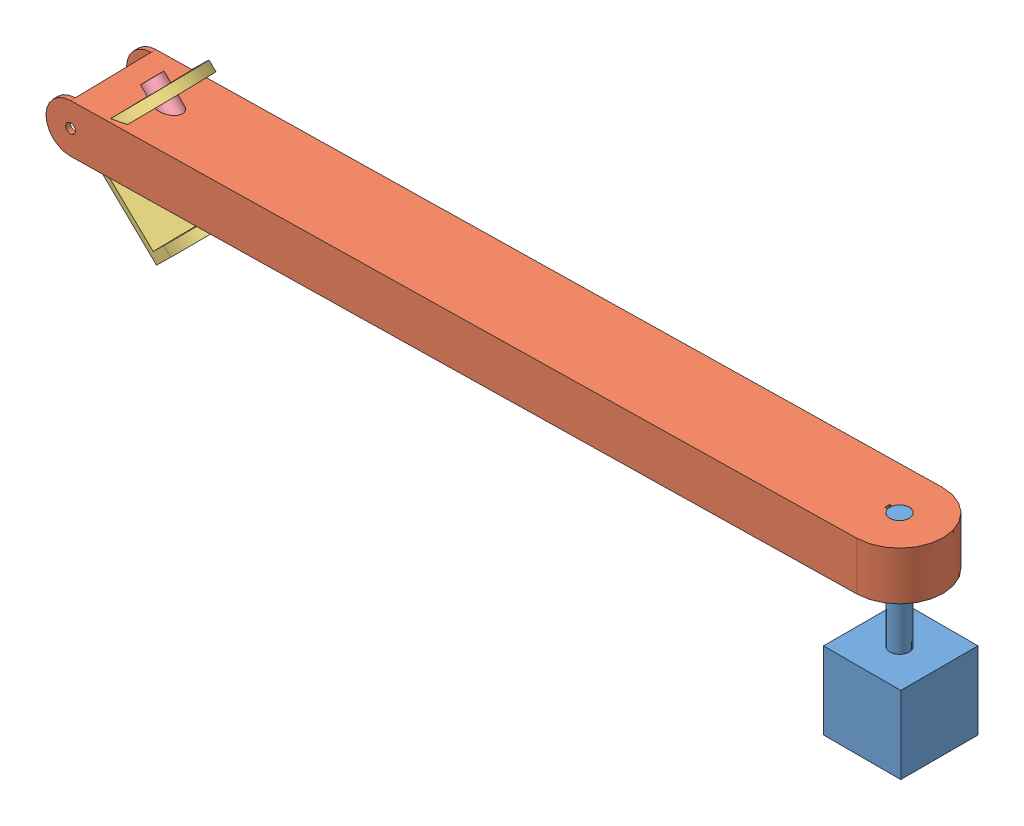
SolidWorks assembly ExcavatorAssm, configuration Default. Lengths in mm.
Overall size (553.4 151.03 78.88).
4 component instances, 4 part files, 6 mates.
Components (placement in the parent):
- joint1barebonesmotor-1: joint1barebonesmotor [Default] at origin size (50.8 127 50.8)
- PreliminaryLink1-1: PreliminaryLink1 [Default] at (-0.1864 110.453 -10.2121) x (0.01825 0 0.999833) z (0 -1 0) size (57.15 552.45 31.75)
- link2pinbracket-1: link2pinbracket [Default] at (-422.7408 90.0407 1.1416) x (-0.208545 -0.225877 0.951572) z (-0.706989 0.707107 0.012905) size (63.5 57.15 69.85)
- link2pin-1: link2pin [Default] at (-428.834 83.8265 7.8276) x (-0.060083 -0.078234 0.995123) z (-0.704668 -0.702766 -0.097796) size (12.7 76.2 12.7)
Mates (geometry in assembly coordinates):
- Concentric1: concentric anti-aligned: cylinder of joint1barebonesmotor-1 through (0 127 0) axis (0 -1 0) radius 6.35; cylinder of PreliminaryLink1-1 through (0 77.2895 0) axis (0 1 0) radius 6.35
- Coincident1: coincident aligned: plane of joint1barebonesmotor-1 through (0 127 0) normal (0 1 0); plane of PreliminaryLink1-1 through (-508.1018 127 -0.941) normal (0 1 0)
- Concentric2: concentric: cylinder of PreliminaryLink1-1 through (158.4346 79.9197 394.3633) axis (0.263601 0.707107 0.656136) radius 6.35; cylinder of link2pin-1 through (-482.7066 137.708 8.8109) axis (0.706989 -0.707107 -0.012905) radius 6.35
- Concentric3: concentric aligned: cylinder of link2pinbracket-1 through (-478.2172 133.2179 8.729) axis (0.706989 -0.707107 -0.012905) radius 6.35; cylinder of link2pin-1 through (-482.7066 137.708 8.8109) axis (0.706989 -0.707107 -0.012905) radius 6.35
- Coincident2: coincident aligned: plane of link2pinbracket-1 through (-439.562 73.1893 2.9515) normal (0.706989 -0.707107 -0.012905); plane of link2pin-1 through (-428.834 83.8265 7.8276) normal (0.706989 -0.707107 -0.012905)
- Distance3: distance = 10.2566 mm: plane of link2pin-1 through (-482.7066 137.708 8.8109) normal (-0.706989 0.707107 0.012905); line of PreliminaryLink1-1 through (-507.4518 127 34.6668) axis (-0.01825 0 -0.999833)
